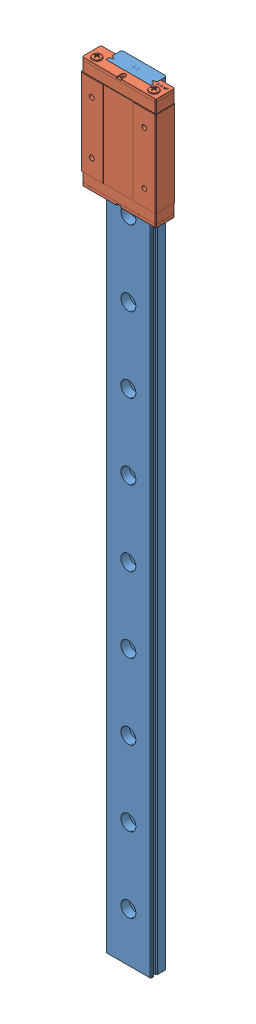
SolidWorks assembly Z-Axis_Hiwin Rail MGW12H1R412Z0HM, configuration Default. Lengths in mm.
2 component instances, 2 part files, 3 mates.
Components (placement in the parent):
- MGW12H1R412Z0HM_FILE(2)-1: MGW12H1R412Z0HM_FILE(2) [Default] at origin size (24 412 8.5)
- MGW12H1R412Z0HM_FILE-1: MGW12H1R412Z0HM_FILE [Default] at (0 306.6001 0) size (40 61.58 10.6)
Mates (geometry in assembly coordinates):
- Concentric1: concentric aligned: cylinder of MGW12H1R412Z0HM_FILE(2)-1 through (-10.7642 412 5.9559) axis (0 -1 0) radius 0.5; cylinder of MGW12H1R412Z0HM_FILE-1 through (-10.7642 432.4611 5.9559) axis (0 -1 0) radius 0.5
- Concentric2: concentric aligned: cylinder of MGW12H1R412Z0HM_FILE(2)-1 through (10.7642 412 5.9559) axis (0 -1 0) radius 0.5; cylinder of MGW12H1R412Z0HM_FILE-1 through (10.7642 432.4611 5.9559) axis (0 -1 0) radius 0.5
- LimitDistance1: limit distance = 352.6011 mm aligned: plane of MGW12H1R412Z0HM_FILE(2)-1 through (-12 0 8.5) normal (0 -1 0); plane of MGW12H1R412Z0HM_FILE-1 through (-19.7 352.6011 13.5) normal (0 -1 0)
